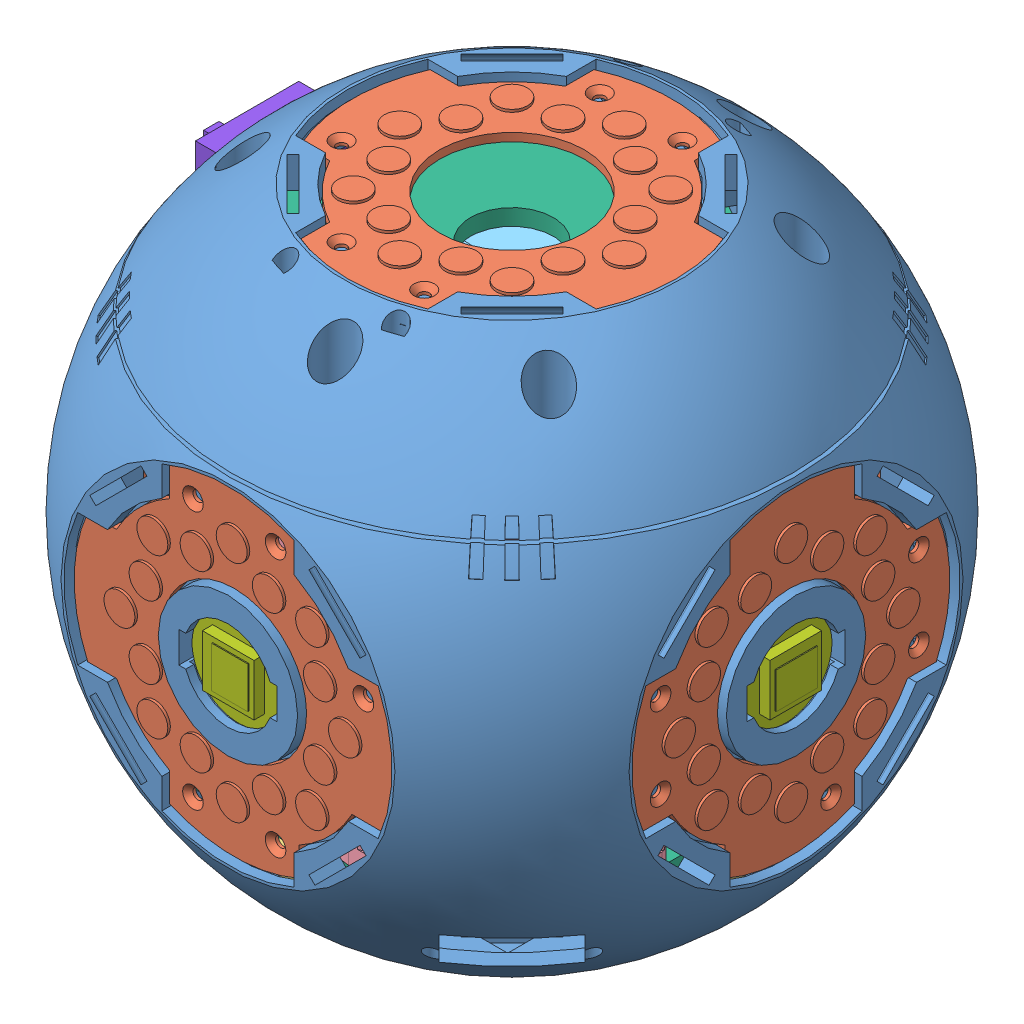
SolidWorks assembly Energy Module, configuration Default. Lengths in mm.
Overall size (63.8 63.8 63.8).
21 component instances, 8 part files, 53 mates.
Components (placement in the parent):
- Cube Shell-3: Cube Shell [Shell for Battery Cube (Large Part)] at origin size (63.8 63.8 63.8)
- Cube Shell-2: Cube Shell [Shell for Battery Cube (Small Part)] at (0 -0.05 0) x (-1 0 0) z (0 0 -1) size (55 59.4 55)
- Face Boards v2-1: Face Boards v2 [Default] at (0 0 26.1) x (1 0 0) z (0 -1 0) size (31 1.04 31)
- Face Boards v2-2: Face Boards v2 [Default] at (26.1 0 0) x (0 -1 0) z (0 0 1) size (31 1.04 31)
- Face Boards v2-3: Face Boards v2 [Default] at (0 0 -26.1) x (1 0 0) z (0 1 0) size (31 1.04 31)
- Face Boards v2-4: Face Boards v2 [Default] at (-26.1 0 0) x (0 1 0) z (0 0 1) size (31 1.04 31)
- Face Boards v2-5: Face Boards v2 [Default] at (0 -26.1 0) x (-1 0 0) z (0 0 1) size (31 1.04 31)
- Face Boards v2-6: Face Boards v2 [Default] at (0 26.05 0) x (-1 0 0) z (0 0 -1) size (31 1.04 31)
- Controller PCB-1: Controller PCB [Default] at (0 -20.2874 0) x (-1 0 0) z (0 0 -1) size (43.18 6.79 43.18)
- Structural Module Internals-2: Structural Module Internals [CR123A v2] at (0 -15.7044 0) size (47 32.45 47)
- CR123A-4: CR123A [Default] at (-4.9075 20.4256 8.5) x (0.736335 0 0.676618) z (0.676618 0 -0.736335) size (17 34.5 17)
- CR123A-5: CR123A [Default] at (-4.9075 19.8539 -8.5) x (-0.503934 0 0.863742) z (0.863742 0 0.503934) size (17 34.5 17)
- CR123A-6: CR123A [Default] at (9.815 -13.4148 0) x (0.570929 0 -0.820999) z (0.820999 0 0.570929) size (17 34.5 17)
- BatteryBoard-1: BatteryBoard [Bottom] at (0 -15.7 0) x (0 0 1) z (-1 0 0) size (50 1.63 50)
- BatteryBoard-3: BatteryBoard [Top] at (0 21.0852 0) x (0 0 1) z (-1 0 0) size (50 6.12 50)
- AdjacencySensor-1: AdjacencySensor [Default] at (0 0 24.9) x (1 0 0) z (0 -1 0) size (9 2.67 9)
- AdjacencySensor-2: AdjacencySensor [Default] at (-24.9 0 0) x (0 1 0) z (0 0 1) size (9 2.67 9)
- AdjacencySensor-3: AdjacencySensor [Default] at (0 0 -24.9) x (1 0 0) z (0 1 0) size (9 2.67 9)
- AdjacencySensor-4: AdjacencySensor [Default] at (0 -24.9 0) x (-0.837169 0 -0.546944) z (-0.546944 0 0.837169) size (9 2.67 9)
- AdjacencySensor-5: AdjacencySensor [Default] at (24.9 0 0) x (0 -1 0) z (0 0 1) size (9 2.67 9)
- Switch-1: Switch [Default] at (-18.6461 19.5 0) x (0 0 -1) z (0 1 0) size (10 7.6 2.5)
Mates (geometry in assembly coordinates):
- Concentric1: concentric aligned: cylinder of Face Boards v2-6 through (0 26.8374 0) axis (0 -1 0) radius 7; circle of Cube Shell-2
- Coincident1: coincident anti-aligned: plane of Cube Shell-2 through (0 26.05 0) normal (0 1 0); plane of Face Boards v2-6 through (0 26.05 0) normal (0 -1 0)
- Parallel1: parallel aligned: line of Cube Shell-2 through (6.4 27.45 -11.6589) axis (0 0 -1); line of Face Boards v2-6 through (6.25 26.8374 -11.399) axis (0 0 -1)
- Concentric2: concentric aligned: cylinder of Cube Shell-3 through (0 0 25.4) axis (0 0 -1) radius 6.75; cylinder of Face Boards v2-1 through (0 0 26.8874) axis (0 0 -1) radius 7
- Coincident3: coincident anti-aligned: plane of Cube Shell-3 through (0 0 26.1) normal (0 0 1); plane of Face Boards v2-1 through (0 0 26.1) normal (0 0 -1)
- Parallel2: parallel aligned: line of Cube Shell-3 through (-11.6589 6.4 27.5) axis (-1 0 0); line of Face Boards v2-1 through (-11.399 6.25 26.8874) axis (-1 0 0)
- Concentric3: concentric aligned: cylinder of Cube Shell-3 through (25.4 0 0) axis (-1 0 0) radius 6.75; cylinder of Face Boards v2-2 through (26.8874 0 0) axis (-1 0 0) radius 7
- Coincident5: coincident anti-aligned: plane of Cube Shell-3 through (26.1 0 0) normal (1 0 0); plane of Face Boards v2-2 through (26.1 0 0) normal (-1 0 0)
- Parallel3: parallel aligned: line of Cube Shell-3 through (27.5 6.4 -14.5465) axis (0 0 1); line of Face Boards v2-2 through (26.8874 6.25 -14.1841) axis (0 0 1)
- Concentric4: concentric aligned: cylinder of Cube Shell-3 through (-25.4 0 0) axis (1 0 0) radius 6.75; cylinder of Face Boards v2-4 through (-26.8874 0 0) axis (1 0 0) radius 7
- Coincident7: coincident anti-aligned: plane of Cube Shell-3 through (-26.1 0 0) normal (-1 0 0); plane of Face Boards v2-4 through (-26.1 0 0) normal (1 0 0)
- Parallel4: parallel aligned: line of Cube Shell-3 through (-27.5 14.5465 -6.4) axis (0 -1 0); line of Face Boards v2-4 through (-26.8874 14.1841 -6.25) axis (0 -1 0)
- Concentric5: concentric aligned: cylinder of Cube Shell-3 through (0 -25.4 0) axis (0 1 0) radius 6.75; cylinder of Face Boards v2-5 through (0 -26.8874 0) axis (0 1 0) radius 7
- Coincident9: coincident anti-aligned: plane of Cube Shell-3 through (0 -26.1 0) normal (0 -1 0); plane of Face Boards v2-5 through (0 -26.1 0) normal (0 1 0)
- Parallel5: parallel anti-aligned: line of Cube Shell-3 through (-14.5465 -27.5 6.4) axis (1 0 0); line of Face Boards v2-5 through (-11.399 -26.8874 6.25) axis (-1 0 0)
- Concentric6: concentric aligned: cylinder of Cube Shell-3 through (0 0 -25.4) axis (0 0 1) radius 6.75; cylinder of Face Boards v2-3 through (0 0 -26.8874) axis (0 0 1) radius 7
- Coincident11: coincident anti-aligned: plane of Cube Shell-3 through (0 0 -26.1) normal (0 0 -1); plane of Face Boards v2-3 through (0 0 -26.1) normal (0 0 1)
- Parallel6: parallel aligned: line of Cube Shell-3 through (14.5465 -6.4 -27.5) axis (-1 0 0); line of Face Boards v2-3 through (14.1841 -6.25 -26.8874) axis (-1 0 0)
- Concentric11: concentric anti-aligned: circle of Cube Shell-3; circle of Controller PCB-1
- Coincident15: coincident aligned: plane of Cube Shell-3 through (0 0 0) normal (0 0 1); plane of assembly through (0 0 0) normal (0 0 1)
- Coincident16: coincident aligned: plane of Cube Shell-3 through (0 0 0) normal (1 0 0); plane of assembly through (0 0 0) normal (1 0 0)
- Coincident17: coincident aligned: plane of Cube Shell-3 through (0 0 0) normal (0 1 0); plane of assembly through (0 0 0) normal (0 1 0)
- Concentric24: concentric aligned: cylinder of Cube Shell-2 through (6.2841 21.16 11.43) axis (0 1 0) radius 0.8033; cylinder of BatteryBoard-3 through (6.2841 21.0852 11.43) axis (0 1 0) radius 1.0033
- Concentric25: concentric aligned: cylinder of Cube Shell-2 through (6.2841 21.16 -11.43) axis (0 1 0) radius 0.8033; cylinder of BatteryBoard-3 through (6.2841 21.0852 -11.43) axis (0 1 0) radius 1.0033
- Coincident29: coincident anti-aligned: plane of Cube Shell-2 through (0 22.66 0) normal (0 -1 0); plane of BatteryBoard-3 through (9.815 22.66 0) normal (0 1 0)
- Concentric26: concentric aligned: cylinder of CR123A-6 through (9.815 21.0852 0) axis (0 1 0) radius 8.5; circle of BatteryBoard-3
- Concentric27: concentric anti-aligned: cylinder of CR123A-5 through (-4.9075 -14.6461 -8.5) axis (0 -1 0) radius 8.5; circle of BatteryBoard-3
- Concentric28: concentric anti-aligned: cylinder of CR123A-4 through (-4.9075 -14.0744 8.5) axis (0 -1 0) radius 8.5; circle of BatteryBoard-3
- Coincident33: coincident anti-aligned: plane of CR123A-6 through (8.6731 21.0852 1.642) normal (0 1 0); plane of BatteryBoard-3 through (9.815 21.0852 0) normal (0 -1 0)
- Concentric32: concentric aligned: circle of Controller PCB-1; circle of BatteryBoard-1
- Concentric33: concentric anti-aligned: circle of Cube Shell-2; cylinder of Structural Module Internals-2 through (-18.5108 -15.7044 7.573) axis (0 1 0) radius 0.8
- Concentric34: concentric aligned: circle of Cube Shell-2; cylinder of Structural Module Internals-2 through (-18.5108 -15.7044 -7.573) axis (0 1 0) radius 0.8
- Coincident37: coincident anti-aligned: circle of Cube Shell-3; plane of Controller PCB-1 through (0 -19.5 0) normal (0 1 0)
- Parallel8: parallel aligned: plane of Cube Shell-3 through (31.0355 -16.5 23.9645) normal (-0.707107 0 0.707107); plane of Controller PCB-1 through (8.0309 -16.5 14.1121) normal (-0.707107 0 0.707107)
- Concentric35: concentric anti-aligned: cylinder of Cube Shell-3 through (-17.6777 -31.9 -17.6777) axis (0 1 0) radius 0.8; cylinder of Structural Module Internals-2 through (-17.6777 -12.3044 -17.6777) axis (0 -1 0) radius 1
- Concentric36: concentric anti-aligned: cylinder of Cube Shell-3 through (17.6777 -31.9 17.6777) axis (0 1 0) radius 0.8; cylinder of Structural Module Internals-2 through (17.6777 -12.3044 17.6777) axis (0 -1 0) radius 1
- Coincident41: coincident anti-aligned: plane of Cube Shell-3 through (0 -15.7 0) normal (0 1 0); plane of BatteryBoard-1 through (0 -15.7 0) normal (0 -1 0)
- Coincident42: coincident anti-aligned: plane of CR123A-4 through (-6.3801 -14.0744 7.1468) normal (0 -1 0); plane of BatteryBoard-1 through (0 -14.0744 0) normal (0 1 0)
- Coincident43: coincident anti-aligned: plane of Structural Module Internals-2 through (0 -14.0744 0) normal (0 -1 0); plane of BatteryBoard-1 through (0 -14.0744 0) normal (0 1 0)
- Parallel9: parallel anti-aligned: plane of Structural Module Internals-2 through (0 -15.7044 0) normal (1 0 0); plane of BatteryBoard-1 through (-22.9226 -14.0744 13.2968) normal (-1 0 0)
- Coincident45: coincident anti-aligned: plane of Cube Shell-3 through (0 0 24.9) normal (0 0 1); plane of AdjacencySensor-1 through (0 0 24.9) normal (0 0 -1)
- Concentric37: concentric aligned: cylinder of Cube Shell-3 through (0 0 26.7) axis (0 0 -1) radius 4.75; cylinder of AdjacencySensor-1 through (0 0 26.4748) axis (0 0 -1) radius 4.5
- Coincident46: coincident anti-aligned: plane of Cube Shell-3 through (-24.9 0 0) normal (-1 0 0); plane of AdjacencySensor-2 through (-24.9 0 0) normal (1 0 0)
- Concentric38: concentric aligned: cylinder of Cube Shell-3 through (-26.7 0 0) axis (1 0 0) radius 4.75; cylinder of AdjacencySensor-2 through (-26.4748 0 0) axis (1 0 0) radius 4.5
- Coincident47: coincident anti-aligned: plane of Cube Shell-3 through (0 -24.9 0) normal (0 -1 0); plane of AdjacencySensor-4 through (0 -24.9 0) normal (0 1 0)
- Concentric39: concentric aligned: cylinder of Cube Shell-3 through (0 -26.7 0) axis (0 1 0) radius 4.75; cylinder of AdjacencySensor-4 through (0 -26.4748 0) axis (0 1 0) radius 4.5
- Coincident48: coincident anti-aligned: plane of Cube Shell-3 through (0 0 -24.9) normal (0 0 -1); plane of AdjacencySensor-3 through (0 0 -24.9) normal (0 0 1)
- Concentric40: concentric aligned: cylinder of Cube Shell-3 through (0 0 -26.7) axis (0 0 1) radius 4.75; cylinder of AdjacencySensor-3 through (0 0 -26.4748) axis (0 0 1) radius 4.5
- Coincident49: coincident anti-aligned: plane of Cube Shell-3 through (24.9 0 0) normal (1 0 0); plane of AdjacencySensor-5 through (24.9 0 0) normal (-1 0 0)
- Concentric41: concentric aligned: cylinder of Cube Shell-3 through (26.7 0 0) axis (-1 0 0) radius 4.75; cylinder of AdjacencySensor-5 through (26.4748 0 0) axis (-1 0 0) radius 4.5
- Coincident50: coincident anti-aligned: plane of Cube Shell-2 through (-27.1177 18.25 -5) normal (0 1 0); plane of Switch-1 through (-25.6461 18.25 5) normal (0 -1 0)
- Coincident51: coincident anti-aligned: plane of Cube Shell-2 through (-27.1177 20.75 5) normal (0 0 -1); plane of Switch-1 through (-25.6461 18.25 5) normal (0 0 1)
- Coincident52: coincident: point of Cube Shell-2; point of Switch-1
